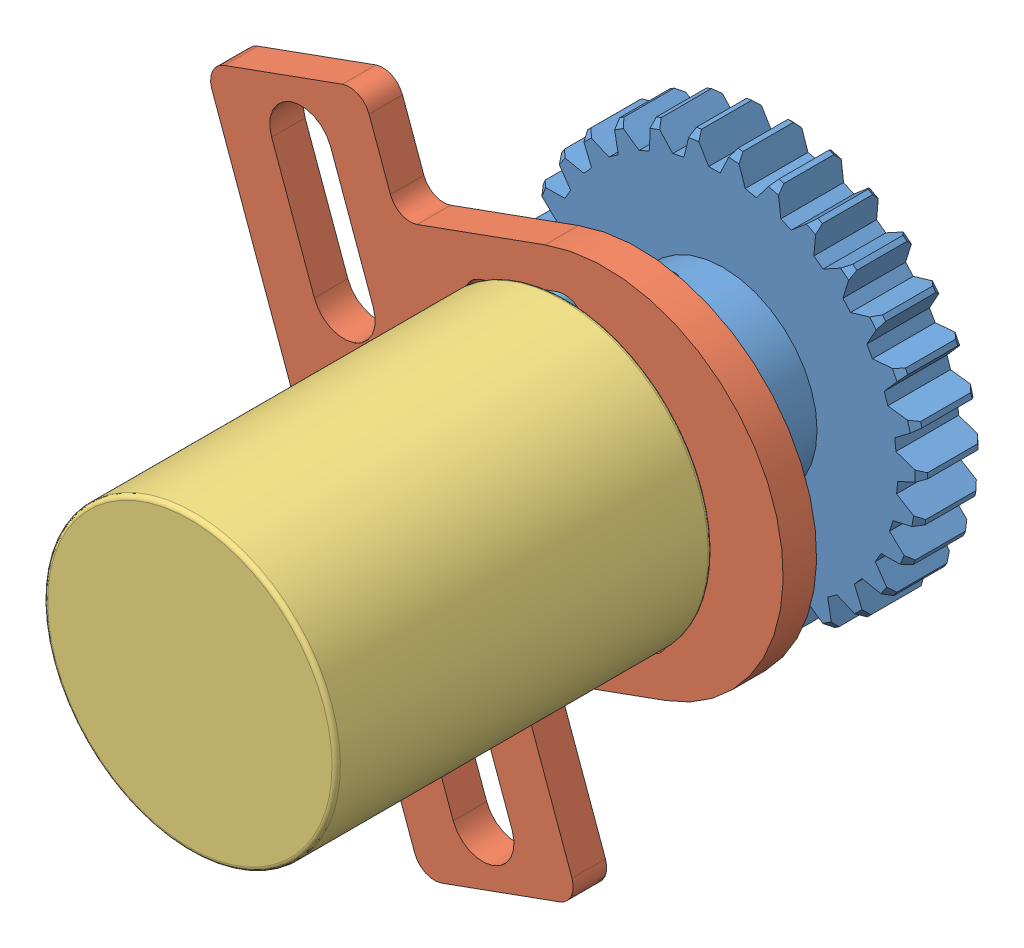
SolidWorks assembly 编码器装配体_左, configuration 默认. Lengths in mm.
Overall size (32.95 36.85 28.5).
6 component instances, 5 part files, 14 mates.
Components (placement in the parent):
- 编码器齿轮-1: 编码器齿轮 [默认] at (-11.2259 7.3482 15.4882) size (18.99 18.98 7)
- 编码器支架-1: 编码器支架 [默认] at (-9.8156 7.859 25.9882) x (-0.940219 -0.340571 0) z (0 0 -1) size (24 30.5 1.6)
- 测速编码器-1: 测速编码器 [默认] at (-11.2259 7.3482 43.9882) x (-0.940219 -0.340571 0) z (0 0 -1) size (14 14 28)
- 紧钉螺钉-M2-1: 紧钉螺钉-M2 [GB_FASTENER_SCREWS_HSCP M2X3-N] at (-12.4134 11.6886 20.5239) x (0.263891 -0.964552 0) z (-0.930361 -0.254537 0.263891) size (3 2 2)
- 十字半圆头螺钉-M2-1: 十字半圆头螺钉-M2 [GB_WOOD_SCREWS_TYPE136 M2X8-N] at (-9.2676 1.9419 22.7882) x (0 0 1) z (-1 0 0) size (6.56 3.9 3.9)
- 十字半圆头螺钉-M2-2: 十字半圆头螺钉-M2 [GB_WOOD_SCREWS_TYPE136 M2X8-N] at (-13.1842 12.7544 22.7882) x (0 0 1) z (-0.927206 -0.374552 0) size (6.56 3.9 3.9)
Mates (geometry in assembly coordinates):
- 重合1: coincident anti-aligned: plane of 编码器支架-1 through (-9.3455 8.0293 25.9882) normal (0 0 1); plane of 测速编码器-1 through (-11.2259 7.3482 25.9882) normal (0 0 -1)
- 同心1: concentric anti-aligned: cylinder of 编码器齿轮-1 through (-11.2259 7.3482 18.4882) axis (0 0 -1) radius 1.5; cylinder of 测速编码器-1 through (-11.2259 7.3482 15.9882) axis (0 0 1) radius 1.5
- 距离1: distance = 0.5 mm aligned: plane of 编码器齿轮-1 through (-11.2259 7.3482 15.4882) normal (0 0 -1); plane of 测速编码器-1 through (-11.2259 7.3482 15.9882) normal (0 0 -1)
- 同心2: concentric aligned: cylinder of 编码器齿轮-1 through (-12.4134 11.6886 20.5239) axis (-0.263891 0.964552 0) radius 0.8; cylinder of 紧钉螺钉-M2-1 through (-16.3122 25.9391 20.5239) axis (-0.263891 0.964552 0) radius 1
- 同心3: concentric aligned: cylinder of 编码器齿轮-1 through (-12.4134 11.6886 20.5239) axis (-0.263891 0.964552 0) radius 0.8; cylinder of 紧钉螺钉-M2-1 through (-16.3122 25.9391 20.5239) axis (-0.263891 0.964552 0) radius 1
- 相切2: tangent anti-aligned: cylinder of 测速编码器-1 through (-11.2259 7.3482 15.9882) axis (0 0 1) radius 1.5; plane of 紧钉螺钉-M2-1 through (-11.6218 8.795 20.5239) normal (0.263891 -0.964552 0)
- 重合3: coincident anti-aligned: plane of 编码器支架-1 through (-9.3455 8.0293 24.3882) normal (0 0 -1); plane of 十字半圆头螺钉-M2-1 through (-8.2676 1.9419 24.3882) normal (0 0 1)
- 相切4: tangent anti-aligned: plane of 编码器支架-1 through (-7.0466 1.6828 24.3882) normal (-0.340571 0.940219 0); cylinder of 十字半圆头螺钉-M2-1 through (-9.2676 1.9419 9.159) axis (0 0 -1) radius 1
- 同心4: concentric aligned: cylinder of 测速编码器-1 through (-9.2676 1.9419 25.9882) axis (0 0 -1) radius 0.8; cylinder of 十字半圆头螺钉-M2-1 through (-9.2676 1.9419 9.159) axis (0 0 -1) radius 1
- 重合4: coincident anti-aligned: plane of 编码器支架-1 through (-9.3455 8.0293 25.9882) normal (0 0 1); plane of 测速编码器-1 through (-11.2259 7.3482 25.9882) normal (0 0 -1)
- 相切5: tangent anti-aligned: plane of 编码器支架-1 through (-10.9632 12.4953 24.3882) normal (-0.340571 0.940219 0); cylinder of 十字半圆头螺钉-M2-2 through (-13.1842 12.7544 9.159) axis (0 0 -1) radius 1
- 重合5: coincident anti-aligned: plane of 编码器支架-1 through (-9.3455 8.0293 24.3882) normal (0 0 -1); plane of 十字半圆头螺钉-M2-2 through (-12.257 13.129 24.3882) normal (0 0 1)
- 同心5: concentric aligned: cylinder of 测速编码器-1 through (-13.1842 12.7544 25.9882) axis (0 0 -1) radius 0.8; cylinder of 十字半圆头螺钉-M2-2 through (-13.1842 12.7544 9.159) axis (0 0 -1) radius 1
- 距离2: distance = 1.5 mm aligned: plane of 测速编码器-1; plane of 编码器支架-1
